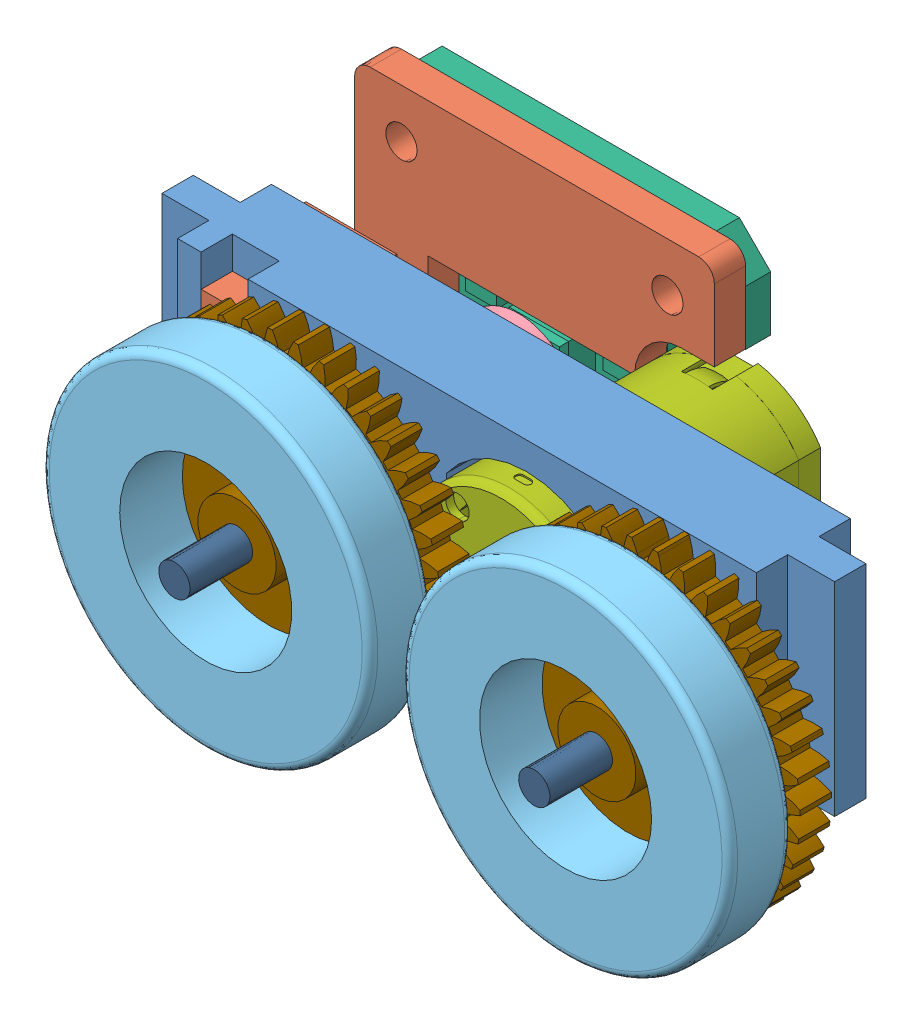
SolidWorks assembly CumBanh2, configuration Default. Lengths in mm.
Overall size (49.55 25.48 26.61).
19 component instances, 12 part files, 38 mates.
Components (placement in the parent):
- Cum Banh 2-1: Cum Banh 2 [Default] at (20.7717 21.8193 30.9365) size (43 13 7.5)
- Ga encoder 2-1: Ga encoder 2 [Default] at (9.0717 24.8497 22.9265) x (1 0 0) z (0 -1 0) size (23 14.1 16.6)
- Ga nam chamV3-1: Ga nam chamV3 [Default] at (32.2717 21.8193 32.4365) x (0 0 -1) z (1 0 0) size (2.5 4.5 4.5)
- Ga nam chamV3.1-1: Ga nam chamV3.1 [Default] at (9.2717 21.8193 32.9365) x (0 0 -1) z (-0.477386 -0.878694 0) size (7 7.5 7.5)
- Lop banh xe-1: Lop banh xe [Default] at (9.2717 21.8193 46.9365) x (0 0 -1) z (0.996149 0.087675 0) size (4 21 21)
- MT6701 Ver2.1-1: MT6701 Ver2.1 [Default] at (9.2717 21.8193 21.3265) x (-1 0 0) z (0 0 1) size (23 17.5 3.61)
- N20 DC MOTOR Truc dai-1: N20 DC MOTOR Truc dai [Default] at (20.7716 21.7399 23.1365) x (0 1 0) z (1 0 0) size (12.48 22.6 10.65)
- Nam cham-1: Nam cham [Default] at (9.2717 21.8193 26.9365) x (0.733421 -0.679775 0) z (0 0 1) size (4 4 2)
- Part4-1: Part4 [Default] at (9.2717 21.8193 40.9365) x (0 0 1) z (-1 0 0) (suppressed, hidden)
- Spur gear 0.5M 38T-1: Spur gear 0.5M 38T [Default] at (9.2717 21.8193 40.9365) x (0 0 -1) z (0.947939 -0.318453 0) size (5 19.95 20)
- Truc 2x20-1: Truc 2x20 [Default] at (9.2717 21.8193 38.9365) size (2 2 18)
- Vong bi 2x5x2.5-1: Vong bi 2x5x2.5 [Default] at (9.2717 21.8193 37.0457) size (5 5 3)
- Vong bi 2x5x2.5-2: Vong bi 2x5x2.5 [Default] at (9.2717 21.8193 40.0457) size (5 5 3)
- Vong bi 2x5x2.5-4: Vong bi 2x5x2.5 [Default] at (32.2717 21.8193 37.0457) x (0.994554 -0.10422 0) z (0 0 1) size (5 5 3)
- Vong bi 2x5x2.5-6: Vong bi 2x5x2.5 [Default] at (32.2717 21.8193 40.0457) size (5 5 3)
- Spur gear 0.5M 38T-2: Spur gear 0.5M 38T [Default] at (32.2717 21.8193 40.9365) x (0 0 -1) z (0.942757 0.333479 0) size (5 19.95 20)
- Lop banh xe-2: Lop banh xe [Default] at (32.2717 21.8193 46.9365) x (0 0 -1) z (1 0 0) size (4 21 21)
- Part4-2: Part4 [Default] at (32.2717 21.8193 40.9365) x (0 0 1) z (-1 0 0) (suppressed, hidden)
- Truc 2x20-2: Truc 2x20 [Default] at (32.2717 21.8193 38.9365) x (-0.98877 0.149444 0) z (0 0 1) size (2 2 18)
Mates (geometry in assembly coordinates):
- Concentric1: concentric anti-aligned: cylinder of Cum Banh 2-1 through (32.2717 21.8193 36.9365) axis (0 0 -1) radius 2.6; cylinder of Vong bi 2x5x2.5-4 through (32.2717 21.8193 37.0457) axis (0 0 1) radius 2.5
- Concentric2: concentric anti-aligned: cylinder of Cum Banh 2-1 through (32.2717 21.8193 36.9365) axis (0 0 -1) radius 2.6; cylinder of Vong bi 2x5x2.5-6 through (32.2717 21.8193 40.0457) axis (0 0 1) radius 2.5
- Concentric4: concentric anti-aligned: cylinder of Cum Banh 2-1 through (32.2717 21.8193 36.9365) axis (0 0 -1) radius 2.6; cylinder of Lop banh xe-2 through (32.2717 21.8193 46.9365) axis (0 0 1) radius 5.5
- Concentric5: concentric aligned: cylinder of Cum Banh 2-1 through (32.2717 21.8193 36.9365) axis (0 0 -1) radius 2.6; cylinder of Part4-2 through (32.2717 21.8193 40.9365) axis (0 0 -1) radius 5.1
- Concentric6: concentric anti-aligned: cylinder of Cum Banh 2-1 through (32.2717 21.8193 36.9365) axis (0 0 -1) radius 2.6; cylinder of Spur gear 0.5M 38T-2 through (32.2717 21.8193 35.9365) axis (0 0 1) radius 1
- Concentric7: concentric aligned: cylinder of Cum Banh 2-1 through (32.2717 21.8193 36.9365) axis (0 0 -1) radius 2.6; cylinder of Truc 2x20-2 through (32.2717 21.8193 47.9365) axis (0 0 -1) radius 1
- Concentric8: concentric anti-aligned: cylinder of Cum Banh 2-1 through (32.2717 21.8193 36.9365) axis (0 0 -1) radius 2.6; cylinder of Ga nam chamV3-1 through (32.2717 21.8193 32.4365) axis (0 0 1) radius 1.1
- Concentric9: concentric anti-aligned: cylinder of Cum Banh 2-1 through (9.2717 21.8193 36.9365) axis (0 0 -1) radius 2.6; cylinder of Vong bi 2x5x2.5-1 through (9.2717 21.8193 37.0457) axis (0 0 1) radius 1
- Concentric10: concentric anti-aligned: cylinder of Cum Banh 2-1 through (9.2717 21.8193 36.9365) axis (0 0 -1) radius 2.6; cylinder of Vong bi 2x5x2.5-2 through (9.2717 21.8193 40.0457) axis (0 0 1) radius 1
- Concentric12: concentric anti-aligned: cylinder of Cum Banh 2-1 through (9.2717 21.8193 36.9365) axis (0 0 -1) radius 2.6; cylinder of Lop banh xe-1 through (9.2717 21.8193 46.9365) axis (0 0 1) radius 5.5
- Concentric13: concentric aligned: cylinder of Cum Banh 2-1 through (9.2717 21.8193 36.9365) axis (0 0 -1) radius 2.6; cylinder of Part4-1 through (9.2717 21.8193 40.9365) axis (0 0 -1) radius 5.1
- Concentric14: concentric anti-aligned: cylinder of Cum Banh 2-1 through (9.2717 21.8193 36.9365) axis (0 0 -1) radius 2.6; cylinder of Spur gear 0.5M 38T-1 through (9.2717 21.8193 35.9365) axis (0 0 1) radius 1
- Concentric15: concentric aligned: cylinder of Cum Banh 2-1 through (9.2717 21.8193 36.9365) axis (0 0 -1) radius 2.6; cylinder of Truc 2x20-1 through (9.2717 21.8193 47.9365) axis (0 0 -1) radius 1
- Concentric16: concentric anti-aligned: cylinder of Cum Banh 2-1 through (9.2717 21.8193 36.9365) axis (0 0 -1) radius 2.6; cylinder of Ga nam chamV3.1-1 through (9.2717 21.8193 32.9365) axis (0 0 1) radius 1.1
- Concentric17: concentric aligned: cylinder of Cum Banh 2-1 through (9.2717 21.8193 36.9365) axis (0 0 -1) radius 2.6; cylinder of Nam cham-1 through (9.2717 21.8193 27.9365) axis (0 0 -1) radius 2
- Concentric18: concentric anti-aligned: cylinder of Cum Banh 2-1 through (9.2717 21.8193 36.9365) axis (0 0 -1) radius 2.6; cylinder of MT6701 Ver2.1-1 through (9.2717 21.8193 16.3265) axis (0 0 1) radius 0.5
- Concentric19: concentric anti-aligned: cylinder of Ga encoder 2-1 through (17.7717 30.3193 24.9265) axis (0 0 -1) radius 1; cylinder of MT6701 Ver2.1-1 through (17.7717 30.3193 17.8265) axis (0 0 1) radius 1
- Concentric20: concentric anti-aligned: cylinder of Ga encoder 2-1 through (0.7717 30.3193 24.9265) axis (0 0 -1) radius 1; cylinder of MT6701 Ver2.1-1 through (0.7717 30.3193 17.8265) axis (0 0 1) radius 1
- Concentric21: concentric aligned: cylinder of N20 DC MOTOR Truc dai-1 through (20.7717 21.8193 38.0365) axis (0 0 -1) radius 5.9205; cylinder of Cum Banh 2-1 through (20.7717 21.8193 36.9365) axis (0 0 -1) radius 6.25
- Parallel1: parallel aligned: plane of N20 DC MOTOR Truc dai-1 through (25.7716 24.9899 38.0365) normal (1 0 0); plane of Cum Banh 2-1 through (15.6717 21.8193 36.9365) normal (1 0 0)
- Coincident2: coincident anti-aligned: plane of Vong bi 2x5x2.5-4 through (32.4802 23.8084 35.9365) normal (0 0 1); plane of Vong bi 2x5x2.5-6 through (32.2717 24.3193 35.9365) normal (0 0 -1)
- Coincident4: coincident anti-aligned: plane of Part4-2 through (39.7717 21.8193 41.9365) normal (0 0 1); plane of Lop banh xe-2 through (32.2717 32.3193 41.9365) normal (0 0 -1)
- Coincident6: coincident anti-aligned: plane of Part4-1 through (16.7717 21.8193 41.9365) normal (0 0 1); plane of Lop banh xe-1 through (8.3511 32.2788 41.9365) normal (0 0 -1)
- Coincident8: coincident anti-aligned: plane of Vong bi 2x5x2.5-1 through (9.2717 23.8193 35.9365) normal (0 0 1); plane of Vong bi 2x5x2.5-2 through (9.2717 24.3193 35.9365) normal (0 0 -1)
- Coincident10: coincident anti-aligned: plane of Ga nam chamV3.1-1 through (11.117 20.8168 27.9365) normal (0 0 -1); plane of Nam cham-1 through (9.2717 21.8193 27.9365) normal (0 0 1)
- Coincident11: coincident anti-aligned: plane of Spur gear 0.5M 38T-2 through (32.2717 21.8193 40.9365) normal (0 0 1); plane of Part4-2 through (34.7717 21.8193 40.9365) normal (0 0 -1)
- Coincident12: coincident anti-aligned: plane of Part4-1 through (11.7717 21.8193 40.9365) normal (0 0 -1); plane of Spur gear 0.5M 38T-1 through (9.2717 21.8193 40.9365) normal (0 0 1)
- Coincident13: coincident anti-aligned: plane of Ga encoder 2-1 through (18.6717 24.8497 22.9265) normal (0 0 -1); plane of MT6701 Ver2.1-1 through (9.2717 21.8193 22.9265) normal (0 0 1)
- Coincident14: coincident aligned: plane of Lop banh xe-1 through (8.3511 32.2788 45.9365) normal (0 0 1); plane of Lop banh xe-2 through (32.2717 32.3193 45.9365) normal (0 0 1)
- Coincident15: coincident aligned: plane of Truc 2x20-1 through (9.2717 21.8193 47.9365) normal (0 0 1); plane of Truc 2x20-2 through (32.2717 21.8193 47.9365) normal (0 0 1)
- Coincident17: coincident anti-aligned: plane of Cum Banh 2-1 through (32.2717 21.8193 32.9365) normal (0 0 1); plane of Vong bi 2x5x2.5-4 through (32.5323 24.3057 32.9365) normal (0 0 -1)
- Coincident18: coincident aligned: plane of Vong bi 2x5x2.5-2 through (9.2717 23.8193 38.9365) normal (0 0 1); plane of Vong bi 2x5x2.5-6 through (32.2717 23.8193 38.9365) normal (0 0 1)
- Coincident19: coincident aligned: plane of Part4-2 through (33.3717 21.8193 47.9365) normal (0 0 1); plane of Truc 2x20-2 through (32.2717 21.8193 47.9365) normal (0 0 1)
- Coincident20: coincident anti-aligned: plane of Ga nam chamV3.1-1 through (9.2717 21.8193 29.9365) normal (0 0 1); plane of Truc 2x20-1 through (9.2717 21.8193 29.9365) normal (0 0 -1)
- Distance1: distance = 1 mm anti-aligned: plane of Nam cham-1 through (9.2717 21.8193 25.9365) normal (0 0 -1); plane of MT6701 Ver2.1-1 through (9.2717 21.8193 24.9365) normal (0 0 1)
- Coincident24: coincident anti-aligned: plane of N20 DC MOTOR Truc dai-1 through (20.7637 21.713 38.9365) normal (0 0 1); plane of Spur gear 0.5M 38T-1 through (9.2717 21.8193 38.9365) normal (0 0 -1)
- Coincident25: coincident aligned: plane of Ga nam chamV3-1 through (32.2717 22.9193 29.9365) normal (0 0 -1); plane of Truc 2x20-2 through (32.2717 21.8193 29.9365) normal (0 0 -1)
- Coincident26: coincident anti-aligned: plane of Spur gear 0.5M 38T-1 through (9.2717 21.8193 38.9365) normal (0 0 -1); plane of Vong bi 2x5x2.5-2 through (9.2717 23.8193 38.9365) normal (0 0 1)
